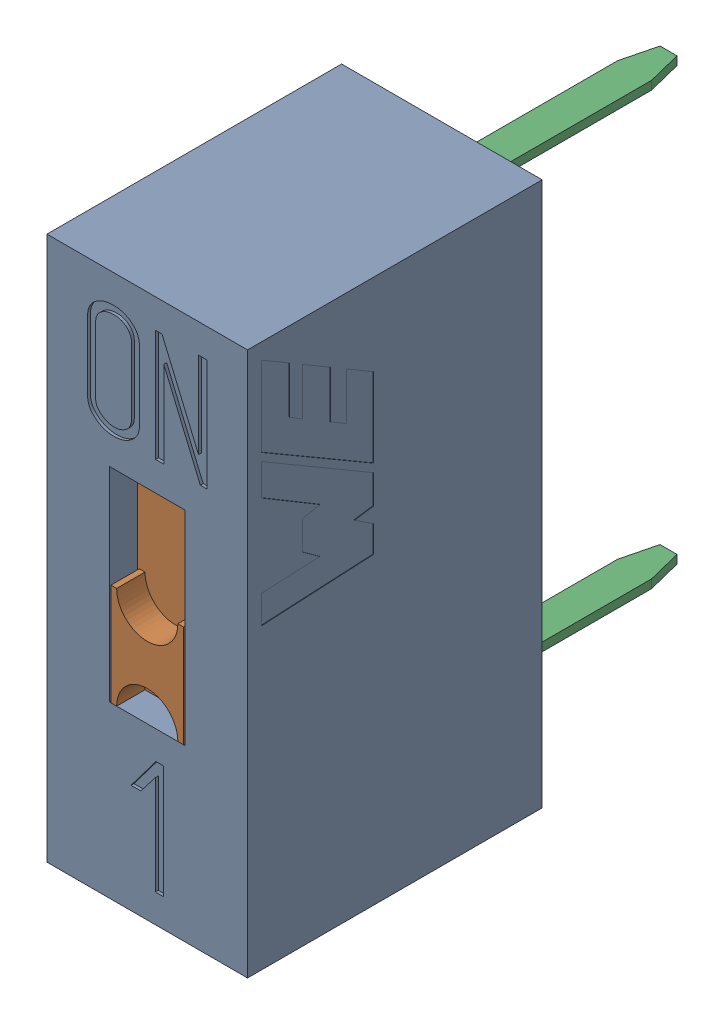
SolidWorks assembly SW1, configuration Default. Lengths in mm.
Overall size (3.54 9.6 9.2).
4 component instances, 3 part files, 0 mates.
Components (placement in the parent):
- 418117170901-1: 418117170901 [Default] at (12.7509 18.8215 0.2) size (3.54 9.6 9.2)
  - Base_switch-1: Base_switch [Default] at origin size (3.54 9.6 5.2)
  - clip-1: clip [Default] at (0 -0.9 4.7) size (2.3 5.8 2.9)
  - base-1: base [Default] at (0 0 0.2) size (2.54 8.7 6.2)
